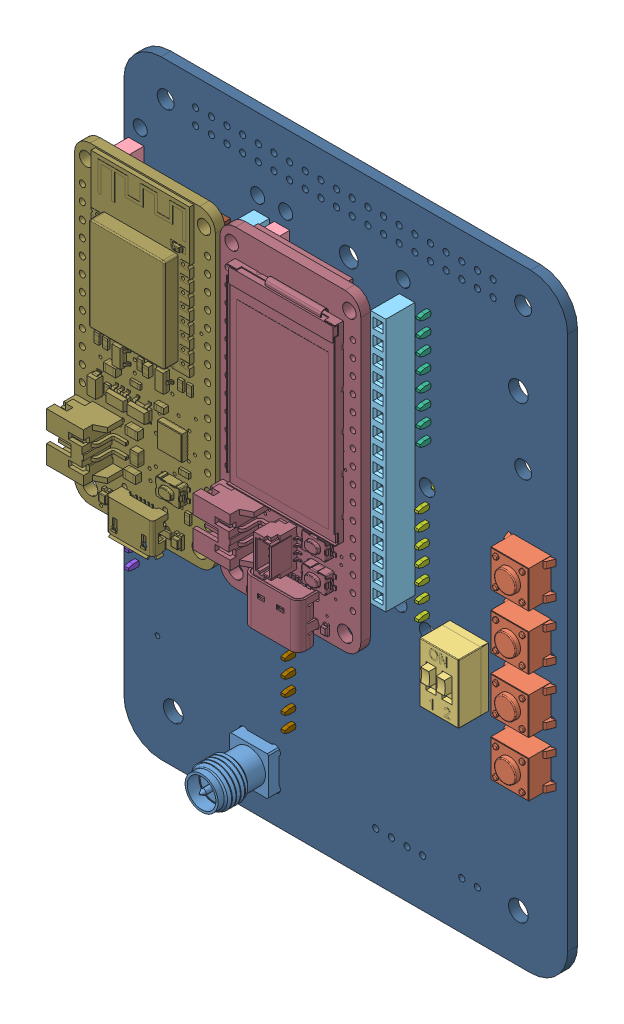
SolidWorks assembly PCB_Assembly, configuration Default. Lengths in mm.
Overall size (72 98.76 19.87).
29 component instances, 13 part files, 37 mates.
Components (placement in the parent):
- CONSMA001-ND-1: CONSMA001-ND [По умолчанию] at (51 -112.776 -2.5) x (1 0 0) z (0 -1 0) size (6.54 13.8 7.33)
- Tactal Switch -Thru (6mmx 6mmx4.5mm)-1: Tactal Switch -Thru (6mmx 6mmx4.5mm) [Default] at (95.2393 -90.1528 1.6) size (8.37 5.99 7.62)
- Tactal Switch -Thru (6mmx 6mmx4.5mm)-2: Tactal Switch -Thru (6mmx 6mmx4.5mm) [Default] at (95.2393 -81.2584 1.6) size (8.37 5.99 7.62)
- Tactal Switch -Thru (6mmx 6mmx4.5mm)-3: Tactal Switch -Thru (6mmx 6mmx4.5mm) [Default] at (95.2393 -72.364 1.6) size (8.37 5.99 7.62)
- Tactal Switch -Thru (6mmx 6mmx4.5mm)-4: Tactal Switch -Thru (6mmx 6mmx4.5mm) [Default] at (95.2393 -63.4696 1.6) size (8.37 5.99 7.62)
- SW-NDS-02V.stp-1: SW-NDS-02V.stp [Default] at (85.025 -82.574 1.219) size (6.35 9.65 8.88)
- 12-Pin Header - Female - 2.54mm.step-1: 12-Pin Header - Female - 2.54mm.step [Default] at (31 -65.41 1.3) x (0 1 0) z (1 0 0) size (30.98 8 2.5)
  - 12er Pin Header Female.step-1: 12er Pin Header Female.step [Default] at (24.13 0 0) size (30.98 8 2.5)
- 16-Pin Header - Female - 2.54mm.step-1: 16-Pin Header - Female - 2.54mm.step [Default] at (51.35 -75.57 1.3) x (0 1 0) z (1 0 0) size (41.14 8 2.5)
  - 16er Pin Header Female.step-1: 16er Pin Header Female.step [Default] at (24.13 0 0) size (41.14 8 2.5)
- 12-Pin Header - Female - 2.54mm.step-2: 12-Pin Header - Female - 2.54mm.step [Default] at (54.65 -65.41 1.3) x (0 1 0) z (1 0 0) size (30.98 8 2.5)
  - 12er Pin Header Female.step-1: 12er Pin Header Female.step [Default] at (24.13 0 0) size (30.98 8 2.5)
- 16-Pin Header - Female - 2.54mm.step-2: 16-Pin Header - Female - 2.54mm.step [Default] at (74.95 -75.57 1.3) x (0 1 0) z (1 0 0) size (41.14 8 2.5)
  - 16er Pin Header Female.step-1: 16er Pin Header Female.step [Default] at (24.13 0 0) size (41.14 8 2.5)
- 8-Pin Header - Female - 2.54mm.step-1: 8-Pin Header - Female - 2.54mm.step [Default] at (78.45 -36.22 0.3) x (0 -1 0) z (1 0 0) size (20.82 8 2.5)
  - 8er Pin Header Female.step-1: 8er Pin Header Female.step [Default] at (24.13 0 0) size (20.82 8 2.5)
- 7-Pin Header - Female - 2.54mm.step-1: 7-Pin Header - Female - 2.54mm.step [Default] at (78.2 -78.73 0.3) x (0 1 0) z (-1 0 0) size (18.28 8 2.5)
  - 7er Pin Header Female.step-1: 7er Pin Header Female.step [Default] at (24.13 0 0) size (18.28 8 2.5)
- 5-Pin Header - Female - 2.54mm.step-1: 5-Pin Header - Female - 2.54mm.step [Default] at (31.1 -95.03 0.3) x (0 1 0) z (-1 0 0) size (13.2 8 2.5)
  - 5er Pin Header Female.step-1: 5er Pin Header Female.step [Default] at (24.13 0 0) size (13.2 8 2.5)
- 9-Pin Header - Female - 2.54mm.step-1: 9-Pin Header - Female - 2.54mm.step [Default] at (56.5 -105.19 0.3) x (0 1 0) z (-1 0 0) size (23.36 8 2.5)
  - 9er Pin Header Female.step-1: 9er Pin Header Female.step [Default] at (24.13 0 0) size (23.36 8 2.5)
- Pioneer Controller-1: Pioneer Controller [Default] at origin size (72 98.76 1.6)
- 15-Pin Header - Female - 2.54mm.step-1: 15-Pin Header - Female - 2.54mm.step [Default] at (45.0498 -76.1859 1.3) x (0.000004 1 0) z (1 -0.000004 0) size (38.6 8 2.5)
  - 15er Pin Header Female.step-1: 15er Pin Header Female.step [Default] at (24.13 0 0) size (38.6 8 2.5)
- 15-Pin Header - Female - 2.54mm.step-2: 15-Pin Header - Female - 2.54mm.step [Default] at (60.3498 -76.186 1.3) x (0.000004 1 0) z (1 -0.000004 0) size (38.6 8 2.5)
  - 15er Pin Header Female.step-1: 15er Pin Header Female.step [Default] at (24.13 0 0) size (38.6 8 2.5)
- Adafruit ESP8266 Feather-4: Adafruit ESP8266 Feather [Default] at (52.61 -81.915 8.8) x (0 1 0) z (0 0 1) size (51.25 22.86 6.37)
- ESP32-S2 TFT Feather-1: ESP32-S2 TFT Feather [Default] at (76.2 -31.115 10.37) x (0 -1 0) z (0 0 -1) size (51.88 22.86 8.92)
Mates (geometry in assembly coordinates):
- Coincident10: coincident aligned: plane of Tactal Switch -Thru (6mmx 6mmx4.5mm)-1 through (98.3 -87.1556 5.2068) normal (1 0 0); plane of Tactal Switch -Thru (6mmx 6mmx4.5mm)-2 through (98.3 -78.2612 5.2068) normal (1 0 0)
- Coincident15: coincident aligned: plane of Tactal Switch -Thru (6mmx 6mmx4.5mm)-2 through (98.3 -78.2612 5.2068) normal (1 0 0); plane of Tactal Switch -Thru (6mmx 6mmx4.5mm)-3 through (98.3 -69.3668 5.2068) normal (1 0 0)
- Coincident16: coincident aligned: plane of Tactal Switch -Thru (6mmx 6mmx4.5mm)-3 through (98.3 -69.3668 5.2068) normal (1 0 0); plane of Tactal Switch -Thru (6mmx 6mmx4.5mm)-4 through (98.3 -60.4724 5.2068) normal (1 0 0)
- Distance3: distance = 2.9 mm anti-aligned: plane of Tactal Switch -Thru (6mmx 6mmx4.5mm)-2 through (98.3 -84.2556 5.2068) normal (0 -1 0); plane of Tactal Switch -Thru (6mmx 6mmx4.5mm)-1 through (92.1786 -87.1556 5.2068) normal (0 1 0)
- Distance4: distance = 2.9 mm anti-aligned: plane of Tactal Switch -Thru (6mmx 6mmx4.5mm)-3 through (98.3 -75.3612 5.2068) normal (0 -1 0); plane of Tactal Switch -Thru (6mmx 6mmx4.5mm)-2 through (92.1786 -78.2612 5.2068) normal (0 1 0)
- Distance5: distance = 2.9 mm anti-aligned: plane of Tactal Switch -Thru (6mmx 6mmx4.5mm)-3 through (92.1786 -69.3668 5.2068) normal (0 1 0); plane of Tactal Switch -Thru (6mmx 6mmx4.5mm)-4 through (98.3 -66.4668 5.2068) normal (0 -1 0)
- Coincident33: coincident aligned: plane of 12-Pin Header - Female - 2.54mm.step-1/12er Pin Header Female.step-1 through (31 -35.95 4.1) normal (0 1 0); plane of 16-Pin Header - Female - 2.54mm.step-1/16er Pin Header Female.step-1 through (51.35 -35.95 4.1) normal (0 1 0)
- Distance13: distance = 17.85 mm anti-aligned: plane of 12-Pin Header - Female - 2.54mm.step-1/12er Pin Header Female.step-1 through (32.25 -66.93 6.3) normal (1 0 0); plane of 16-Pin Header - Female - 2.54mm.step-1/16er Pin Header Female.step-1 through (50.1 -77.09 1.3) normal (-1 0 0)
- Distance18: distance = 6.45 mm anti-aligned: plane of 8-Pin Header - Female - 2.54mm.step-1/8er Pin Header Female.step-1 through (78.45 -55.52 -2.5) normal (0 -1 0); plane of 7-Pin Header - Female - 2.54mm.step-1/7er Pin Header Female.step-1 through (78.2 -61.97 -2.5) normal (0 1 0)
- Coincident52: coincident aligned: plane of 5-Pin Header - Female - 2.54mm.step-1/5er Pin Header Female.step-1 through (31.1 -83.35 -2.5) normal (0 1 0); plane of 9-Pin Header - Female - 2.54mm.step-1/9er Pin Header Female.step-1 through (56.5 -83.35 -2.5) normal (0 1 0)
- Distance22: distance = 22.9 mm anti-aligned: plane of 9-Pin Header - Female - 2.54mm.step-1/9er Pin Header Female.step-1 through (55.25 -106.71 -4.7) normal (-1 0 0); plane of 5-Pin Header - Female - 2.54mm.step-1/5er Pin Header Female.step-1 through (32.35 -96.55 0.3) normal (1 0 0)
- Coincident54: coincident anti-aligned: plane of 12-Pin Header - Female - 2.54mm.step-1/12er Pin Header Female.step-1 through (30 -66.93 1.6) normal (0 0 -1); plane of Pioneer Controller-1 through (64.9999 -71.3787 1.6) normal (0 0 1)
- Coincident55: coincident anti-aligned: plane of 16-Pin Header - Female - 2.54mm.step-1/16er Pin Header Female.step-1 through (50.35 -77.09 1.6) normal (0 0 -1); plane of Pioneer Controller-1 through (64.9999 -71.3787 1.6) normal (0 0 1)
- Coincident56: coincident anti-aligned: plane of 12-Pin Header - Female - 2.54mm.step-2/12er Pin Header Female.step-1 through (53.65 -66.93 1.6) normal (0 0 -1); plane of Pioneer Controller-1 through (64.9999 -71.3787 1.6) normal (0 0 1)
- Coincident57: coincident anti-aligned: plane of 16-Pin Header - Female - 2.54mm.step-2/16er Pin Header Female.step-1 through (73.95 -77.09 1.6) normal (0 0 -1); plane of Pioneer Controller-1 through (64.9999 -71.3787 1.6) normal (0 0 1)
- Coincident58: coincident anti-aligned: plane of 9-Pin Header - Female - 2.54mm.step-1/9er Pin Header Female.step-1 through (57.5 -106.71 0) normal (0 0 1); plane of Pioneer Controller-1 through (64.9999 -71.3787 0) normal (0 0 -1)
- Coincident59: coincident anti-aligned: plane of 5-Pin Header - Female - 2.54mm.step-1/5er Pin Header Female.step-1 through (32.1 -96.55 0) normal (0 0 1); plane of Pioneer Controller-1 through (64.9999 -71.3787 0) normal (0 0 -1)
- Coincident60: coincident anti-aligned: plane of 7-Pin Header - Female - 2.54mm.step-1/7er Pin Header Female.step-1 through (79.2 -80.25 0) normal (0 0 1); plane of Pioneer Controller-1 through (64.9999 -71.3787 0) normal (0 0 -1)
- Coincident61: coincident anti-aligned: plane of 8-Pin Header - Female - 2.54mm.step-1/8er Pin Header Female.step-1 through (77.45 -34.7 0) normal (0 0 1); plane of Pioneer Controller-1 through (64.9999 -71.3787 0) normal (0 0 -1)
- Coincident62: coincident anti-aligned: plane of Tactal Switch -Thru (6mmx 6mmx4.5mm)-4 through (95.2393 -63.4696 1.6) normal (0 0 -1); plane of Pioneer Controller-1 through (64.9999 -71.3787 1.6) normal (0 0 1)
- Coincident63: coincident anti-aligned: plane of Tactal Switch -Thru (6mmx 6mmx4.5mm)-3 through (95.2393 -72.364 1.6) normal (0 0 -1); plane of Pioneer Controller-1 through (64.9999 -71.3787 1.6) normal (0 0 1)
- Coincident64: coincident anti-aligned: plane of Tactal Switch -Thru (6mmx 6mmx4.5mm)-2 through (95.2393 -81.2584 1.6) normal (0 0 -1); plane of Pioneer Controller-1 through (64.9999 -71.3787 1.6) normal (0 0 1)
- Coincident65: coincident anti-aligned: plane of Tactal Switch -Thru (6mmx 6mmx4.5mm)-1 through (95.2393 -90.1528 1.6) normal (0 0 -1); plane of Pioneer Controller-1 through (64.9999 -71.3787 1.6) normal (0 0 1)
- Coincident66: coincident anti-aligned: plane of SW-NDS-02V.stp-1 through (81.85 -87.4 1.6) normal (0 0 -1); plane of Pioneer Controller-1 through (64.9999 -71.3787 1.6) normal (0 0 1)
- Coincident67: coincident anti-aligned: plane of CONSMA001-ND-1 through (48.325 -112.776 1.6) normal (0 0 -1); plane of Pioneer Controller-1 through (64.9999 -71.3787 1.6) normal (0 0 1)
- Concentric1: concentric anti-aligned: cylinder of CONSMA001-ND-1 through (51 -112.776 -1002.5) axis (0 0 -1) radius 0.635; cylinder of Pioneer Controller-1 through (51 -112.776 -0.8) axis (0 0 1) radius 0.75
- Coincident68: coincident anti-aligned: plane of Pioneer Controller-1 through (64.9999 -71.3787 1.6) normal (0 0 1); plane of 15-Pin Header - Female - 2.54mm.step-1/15er Pin Header Female.step-1 through (44.0498 -77.7059 1.6) normal (0 0 -1)
- Coincident69: coincident anti-aligned: plane of Pioneer Controller-1 through (64.9999 -71.3787 1.6) normal (0 0 1); plane of 15-Pin Header - Female - 2.54mm.step-2/15er Pin Header Female.step-1 through (59.3498 -77.706 1.6) normal (0 0 -1)
- Distance23: distance = 14.8 mm aligned: plane of 15-Pin Header - Female - 2.54mm.step-1/15er Pin Header Female.step-1 through (43.7998 -77.7059 1.3) normal (-1 0.000004 0); plane of Pioneer Controller-1 through (28.9997 -114.7574 0) normal (-1 0.000004 0)
- Distance25: distance = 30.1 mm aligned: plane of Pioneer Controller-1 through (28.9997 -114.7574 0) normal (-1 0.000004 0); plane of 15-Pin Header - Female - 2.54mm.step-2/15er Pin Header Female.step-1 through (59.0998 -77.706 1.3) normal (-1 0.000004 0)
- Coincident79: coincident aligned: plane of 15-Pin Header - Female - 2.54mm.step-1/15er Pin Header Female.step-1 through (45.05 -39.1059 4.1) normal (0.000004 1 0); plane of 15-Pin Header - Female - 2.54mm.step-2/15er Pin Header Female.step-1 through (60.35 -39.106 4.1) normal (0.000004 1 0)
- Distance26: distance = 2.5 mm anti-aligned: plane of Adafruit ESP8266 Feather-4 through (41.18 -56.515 8.8) normal (0 0 -1); plane of 12-Pin Header - Female - 2.54mm.step-1/12er Pin Header Female.step-1 through (29.75 -66.93 6.3) normal (0 0 1)
- Concentric2: concentric anti-aligned: cylinder of Pioneer Controller-1 through (50.07 -79.375 0) axis (0 0 -1) radius 1.27; cylinder of Adafruit ESP8266 Feather-4 through (50.07 -79.375 8.8) axis (0 0 1) radius 1.25
- Concentric3: concentric anti-aligned: cylinder of Pioneer Controller-1 through (32.29 -79.375 0) axis (0 0 -1) radius 1.27; cylinder of Adafruit ESP8266 Feather-4 through (32.29 -79.375 8.8) axis (0 0 1) radius 1.25
- Distance27: distance = 2.5 mm anti-aligned: plane of 16-Pin Header - Female - 2.54mm.step-2/16er Pin Header Female.step-1 through (73.7 -77.09 6.3) normal (0 0 1); plane of ESP32-S2 TFT Feather-1 through (64.77 -56.515 8.8) normal (0 0 -1)
- Concentric5: concentric anti-aligned: cylinder of Pioneer Controller-1 through (55.88 -79.375 -0.8) axis (0 0 1) radius 1.27; cylinder of ESP32-S2 TFT Feather-1 through (55.88 -79.375 10.37) axis (0 0 -1) radius 1.25
- Concentric6: concentric anti-aligned: cylinder of Pioneer Controller-1 through (73.66 -79.375 -0.8) axis (0 0 1) radius 1.27; cylinder of ESP32-S2 TFT Feather-1 through (73.66 -79.375 10.37) axis (0 0 -1) radius 1.25
